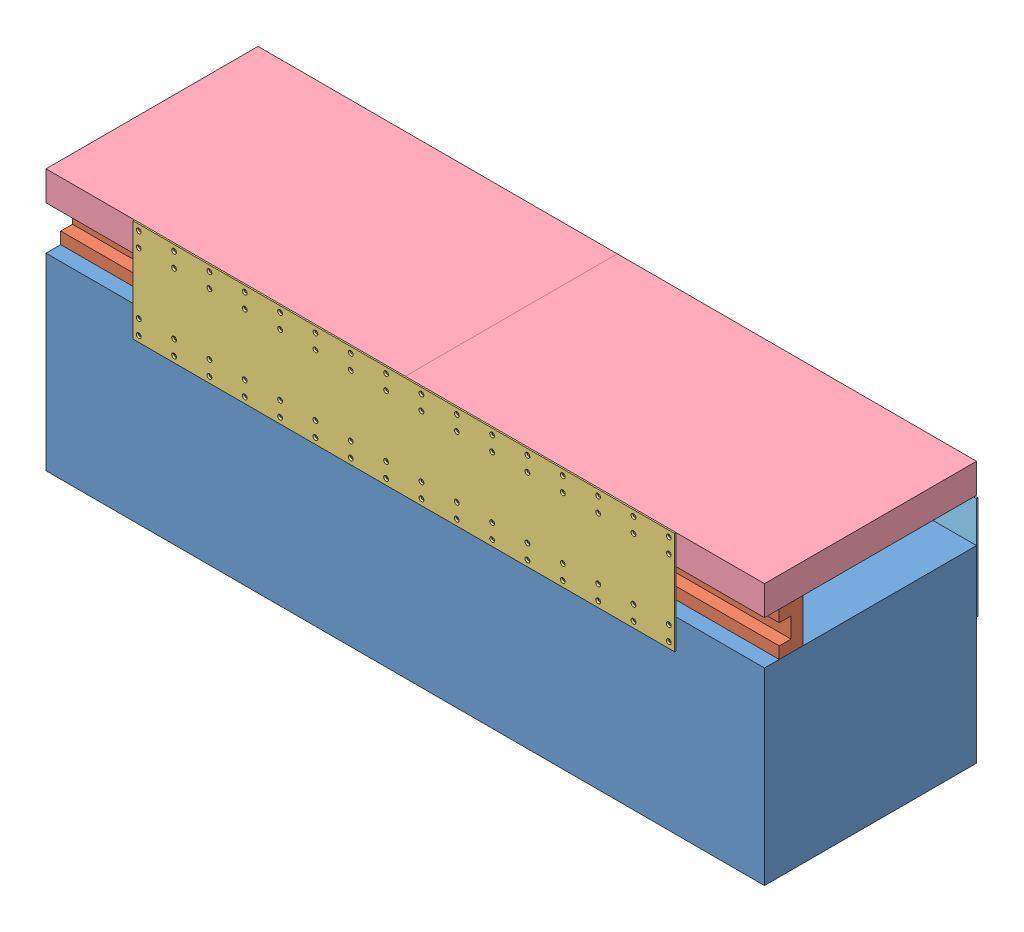
SolidWorks assembly Treadmill_Modified, configuration Default. Lengths in mm.
Overall size (1549.4 563.88 463.55).
6 component instances, 6 part files, 15 mates.
Components (placement in the parent):
- Bottom Structure-1: Bottom Structure [Default] at (-36.3622 887.427 1417.9446) size (1549.4 406.4 457.2)
- C_Channel-1: C_Channel [Default] at (-36.3622 887.427 1386.1946) size (1549.4 93.98 50.8)
- Supporting Side Plate_Modified-1: Supporting Side Plate_Modified [Default] at (154.1378 823.927 1421.1196) size (1168.4 220.98 3.17)
- Top Structure-1: Top Structure [Default] at (-36.3622 981.407 1417.9446) size (1549.4 63.5 457.2)
- Supporting Bracket Rear_Modified-1: Supporting Bracket Rear_Modified [Default] at (1513.0378 754.077 960.7446) size (129.54 284.48 3.17)
- Supporting Bracket Front_Modified-1: Supporting Bracket Front_Modified [Default] at (-36.3622 754.077 960.7446) size (129.54 284.48 3.17)
Mates (geometry in assembly coordinates):
- Coincident1: coincident anti-aligned: plane of Bottom Structure-1 through (-36.3622 887.427 1417.9446) normal (0 1 0); plane of C_Channel-1 through (1513.0378 887.427 1386.1946) normal (0 -1 0)
- Coincident2: coincident aligned: plane of Bottom Structure-1 through (1513.0378 481.027 1417.9446) normal (1 0 0); plane of C_Channel-1 through (1513.0378 887.427 1386.1946) normal (1 0 0)
- Distance1: distance = 31.75 mm aligned: plane of C_Channel-1 through (1513.0378 887.427 1386.1946) normal (0 0 1); plane of Bottom Structure-1 through (-36.3622 481.027 1417.9446) normal (0 0 1)
- Coincident4: coincident aligned: plane of C_Channel-1 through (1513.0378 887.427 1386.1946) normal (1 0 0); plane of Top Structure-1 through (1513.0378 981.407 960.7446) normal (1 0 0)
- Coincident5: coincident aligned: plane of Bottom Structure-1 through (-36.3622 481.027 1417.9446) normal (0 0 1); plane of Top Structure-1 through (-36.3622 981.407 1417.9446) normal (0 0 1)
- Coincident6: coincident anti-aligned: plane of C_Channel-1 through (1513.0378 981.407 1335.3946) normal (0 1 0); plane of Top Structure-1 through (-36.3622 981.407 960.7446) normal (0 -1 0)
- Coincident7: coincident anti-aligned: plane of Bottom Structure-1 through (-36.3622 481.027 1417.9446) normal (0 0 1); plane of Supporting Side Plate_Modified-1 through (154.1378 823.927 1417.9446) normal (0 0 -1)
- Distance2: distance = 190.5 mm aligned: plane of Supporting Side Plate_Modified-1 through (1322.5378 823.927 1417.9446) normal (1 0 0); plane of Bottom Structure-1 through (1513.0378 481.027 1417.9446) normal (1 0 0)
- Coincident9: coincident aligned: plane of Supporting Side Plate_Modified-1 through (154.1378 1044.907 1417.9446) normal (0 1 0); plane of Top Structure-1 through (-36.3622 1044.907 960.7446) normal (0 1 0)
- Coincident10: coincident aligned: plane of Bottom Structure-1 through (1513.0378 481.027 1417.9446) normal (1 0 0); plane of Supporting Bracket Rear_Modified-1 through (1513.0378 754.077 957.5696) normal (1 0 0)
- Distance3: distance = 6.35 mm aligned: plane of Top Structure-1 through (-36.3622 1044.907 960.7446) normal (0 1 0); plane of Supporting Bracket Rear_Modified-1 through (1500.3378 1038.557 957.5696) normal (0 1 0)
- Coincident12: coincident aligned: plane of Bottom Structure-1 through (-36.3622 481.027 1417.9446) normal (-1 0 0); plane of Supporting Bracket Front_Modified-1 through (-36.3622 754.077 957.5696) normal (-1 0 0)
- Distance4: distance = 6.35 mm aligned: plane of Supporting Bracket Front_Modified-1 through (-23.6622 1038.557 957.5696) normal (0 1 0); plane of Top Structure-1 through (-36.3622 1044.907 960.7446) normal (0 1 0)
- Coincident15: coincident anti-aligned: plane of Top Structure-1 through (-36.3622 981.407 960.7446) normal (0 0 -1); plane of Supporting Bracket Front_Modified-1 through (-30.0122 981.407 960.7446) normal (0 0 1)
- Coincident16: coincident anti-aligned: plane of Bottom Structure-1 through (-36.3622 481.027 960.7446) normal (0 0 -1); plane of Supporting Bracket Rear_Modified-1 through (1506.6878 981.407 960.7446) normal (0 0 1)
